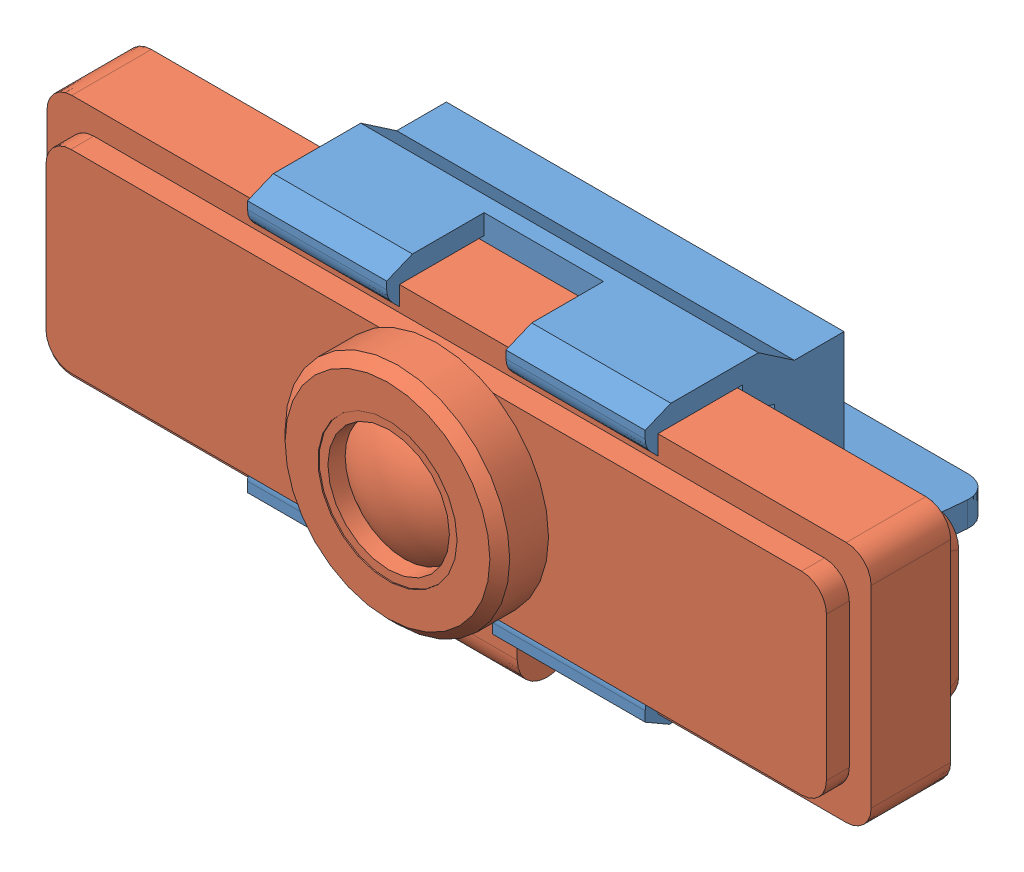
SolidWorks assembly 2018-317-A, configuration Default. Lengths in mm.
Overall size (105.28 41.66 52.26).
2 component instances, 2 part files, 4 mates.
Components (placement in the parent):
- 2018-301-D029-1: 2018-301-D029 [Default] at (-25.4 18.4581 -23.1517) size (50.8 35.42 44.38)
- 2018-301-D030-1: 2018-301-D030 [Default] at origin size (105.28 39.12 33.99)
Mates (geometry in assembly coordinates):
- Coincident1: coordinate: point of 2018-301-D030-1; point of assembly
- Coincident2: coincident aligned: plane of 2018-301-D029-1 through (0 18.4581 -23.1517) normal (1 0 0); plane of assembly through (0 0 0) normal (1 0 0)
- Coincident3: coincident anti-aligned: plane of 2018-301-D029-1 through (25.4 11.303 -9.8044) normal (0 0 1); plane of 2018-301-D030-1 through (0 0 -9.8044) normal (0 0 -1)
- Coincident4: coincident anti-aligned: plane of 2018-301-D029-1 through (25.4 15.494 -5.7404) normal (0 -1 0); plane of 2018-301-D030-1 through (-52.6415 15.494 5.08) normal (0 1 0)
